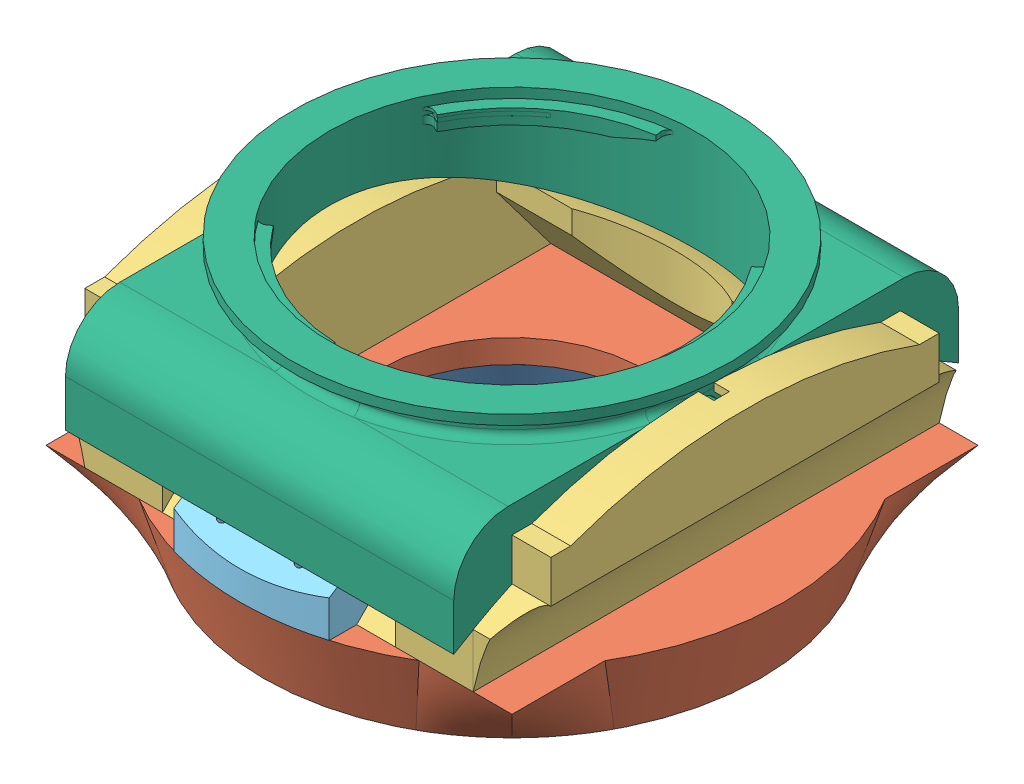
SolidWorks assembly final assembly, configuration Default. Lengths in mm.
Overall size (75.87 37.43 75.87).
7 component instances, 6 part files, 18 mates.
Components (placement in the parent):
- pc0-1: pc0 [Default] at (-447.8438 0 0) x (1 0 0) z (0 0 -1) size (54 11.1 54)
- pc1.1-1: pc1.1 [Default] at (-447.8438 3 0) x (0 0 1) z (1 0 0) size (70 12.1 70)
- pc 2-2: pc 2 [Default] at (-447.8438 3 0) x (0 0 1) z (-1 0 0) size (60.63 19 60.63)
- base ring-1: base ring [Default] at (-447.8438 -7 0) x (0.782747 0 -0.62234) z (0.62234 0 0.782747) size (54 3 54)
- slides-1: slides [Default] at (-447.8438 3 0) x (0 0 -1) z (-1 0 0) size (35 19.54 20)
- slides-2: slides [Default] at (-447.8438 3 0) x (0 0 1) z (1 0 0) size (35 19.54 20)
- pc3.3-1: pc3.3 [Default] at (-440.4161 14.4356 13.0914) x (0 0 1) z (-1 0 0) size (65 17.9 56.26)
Mates (geometry in assembly coordinates):
- Coincident18: coincident anti-aligned: plane of pc0-1 through (-447.8438 0 0) normal (0 1 0); plane of pc1.1-1 through (-447.8438 0 0) normal (0 -1 0)
- Concentric3: concentric anti-aligned: cylinder of pc0-1 through (-447.8438 0 0) axis (0 1 0) radius 22; cylinder of base ring-1 through (-447.8438 -4 0) axis (0 -1 0) radius 27
- Coincident23: coincident aligned: plane of pc1.1-1 through (-447.8438 -7 0) normal (0 -1 0); plane of base ring-1 through (-447.8438 -7 0) normal (0 -1 0)
- Coincident56: coincident aligned: plane of pc1.1-1; plane of assembly through (0 0 0) normal (0 0 1)
- Concentric18: concentric aligned: circle of pc0-1; circle of pc1.1-1
- Coincident29: coincident anti-aligned: plane of pc1.1-1 through (-447.8438 3 0) normal (0 1 0); plane of slides-1 through (-487.8438 3 -35) normal (0 -1 0)
- Coincident31: coincident anti-aligned: plane of pc1.1-1 through (-447.8438 3 0) normal (0 1 0); plane of slides-2 through (-407.8438 3 35) normal (0 -1 0)
- Coincident41: coincident anti-aligned: plane of pc 2-2 through (-432.8438 18 -15) normal (0 0.707107 -0.707107); plane of slides-1 through (-487.8438 3 -30) normal (0 -0.707107 0.707107)
- Coincident47: coincident anti-aligned: plane of pc 2-2 through (-432.8438 18 -15) normal (0 0.707107 -0.707107); plane of slides-1 through (-487.8438 3 -30) normal (0 -0.707107 0.707107)
- Coincident48: coincident anti-aligned: plane of pc 2-2 through (-432.8438 18 15) normal (0 0.707107 0.707107); plane of slides-2 through (-407.8438 3 30) normal (0 -0.707107 -0.707107)
- Coincident49: coincident anti-aligned: plane of pc1.1-1 through (-447.8438 3 0) normal (0 1 0); plane of slides-2 through (-407.8438 3 35) normal (0 -1 0)
- Concentric21: concentric anti-aligned: cylinder of pc1.1-1 through (-452.8438 -2 32) axis (0 1 0) radius 0.75; cylinder of slides-2 through (-452.8438 12.5436 32) axis (0 -1 0) radius 0.75
- Concentric20: concentric anti-aligned: cylinder of pc1.1-1 through (-442.8438 -2 32) axis (0 1 0) radius 0.75; cylinder of slides-2 through (-442.8438 12.5436 32) axis (0 -1 0) radius 0.75
- Concentric23: concentric anti-aligned: cylinder of pc1.1-1 through (-442.8438 -2 -32) axis (0 1 0) radius 0.75; cylinder of slides-1 through (-442.8438 12.5436 -32) axis (0 -1 0) radius 0.75
- Concentric24: concentric anti-aligned: cylinder of pc 2-2 through (-472.8438 -42 0) axis (1 0 0) radius 60; cylinder of pc3.3-1 through (-422.8438 -42 0) axis (-1 0 0) radius 60
- Coincident57: coincident anti-aligned: plane of pc 2-2 through (-422.8438 3 0) normal (-1 0 0); plane of pc3.3-1 through (-422.8438 14.4356 13.0914) normal (1 0 0)
- Coincident45: coincident: point of pc 2-2; point of pc1.1-1
- Concentric25: concentric anti-aligned: circle of pc1.1-1; circle of pc3.3-1
